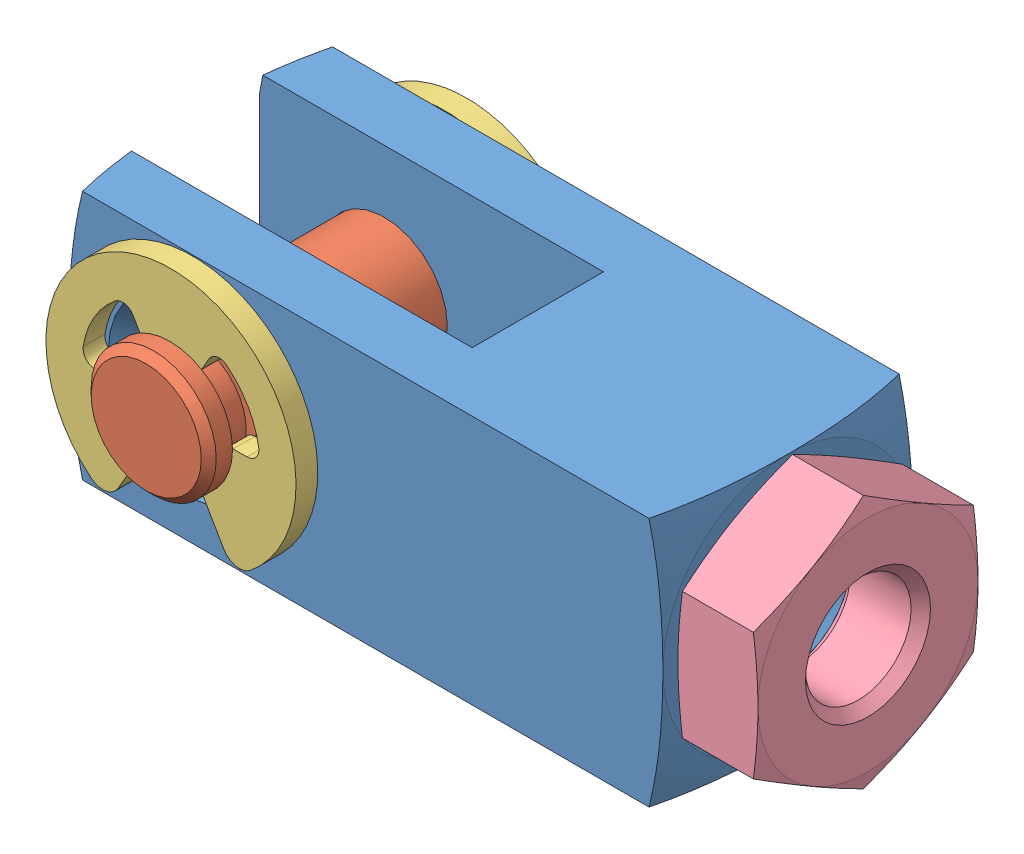
SolidWorks assembly D-166-3, configuration Default. Lengths in mm.
Overall size (35.1 12.9 17.53).
5 component instances, 4 part files, 0 mates.
Components (placement in the parent):
- _D-14055-1: _D-14055 [Default] x (1 0 0) z (0 0 -1) size (31.89 12.7 12.7)
- _D-8381-1: _D-8381 [Default] x (0 0 1) z (-1 0 0) size (17.53 6.35 6.35)
- _D-5866-1: _D-5866 [Default] at (0 0 6.9533) x (-1 0 0) z (0 0 -1) size (12.7 11.45 1.1)
- _D-5866-2: _D-5866 [Default] at (0 0 -6.9533) x (-1 0 0) z (0 0 -1) size (12.7 11.45 1.1)
- _D-344-1: _D-344 [Default] at (23.8252 0 0) x (0 0 1) z (-1 0 0) size (11.18 12.9 4.06)
